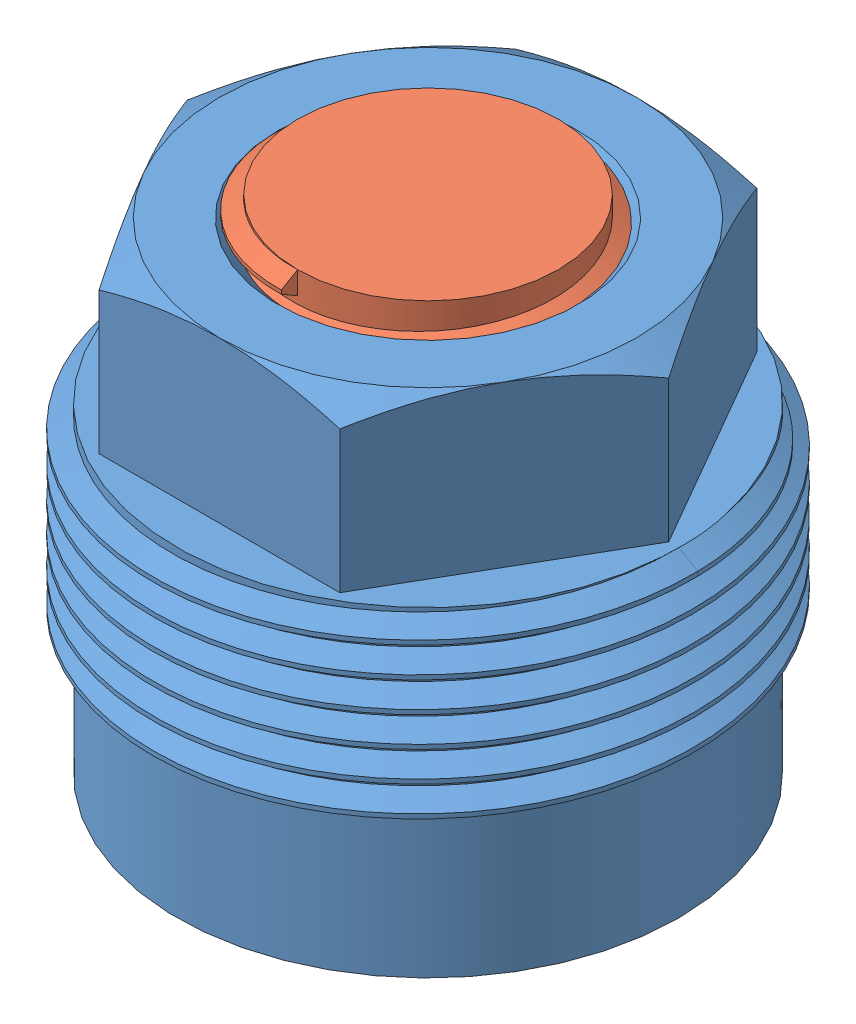
SolidWorks assembly Сборка4, configuration По умолчанию. Lengths in mm.
Overall size (26.9 25 26.9).
2 component instances, 2 part files, 3 mates.
Components (placement in the parent):
- Гайка-1: Гайка [По умолчанию] at (-17.3232 15.2586 -6.4818) x (-1 0 0) z (0 1 0) size (26.9 26.9 24.02)
- Вставная штука 2-2: Вставная штука 2 [По умолчанию] at (-17.3232 25.7586 -6.4818) x (-1 0 0) z (0 0 -1) size (20 18.5 20)
Mates (geometry in assembly coordinates):
- Концентричный4: concentric aligned: circle of Гайка-1; circle of Вставная штука 2-2
- Совпадение8: coincident anti-aligned: plane of Гайка-1 through (-17.3232 31.2586 -6.4818) normal (0 -1 0); plane of Вставная штука 2-2 through (-17.3232 31.2586 -6.4818) normal (0 1 0)
- Параллельность2: parallel anti-aligned: plane of Гайка-1 through (-24.6351 31.8211 -6.4818) normal (0 0 1); plane of Вставная штука 2-2 through (-24.6351 31.8211 -6.4818) normal (0 0 -1)
